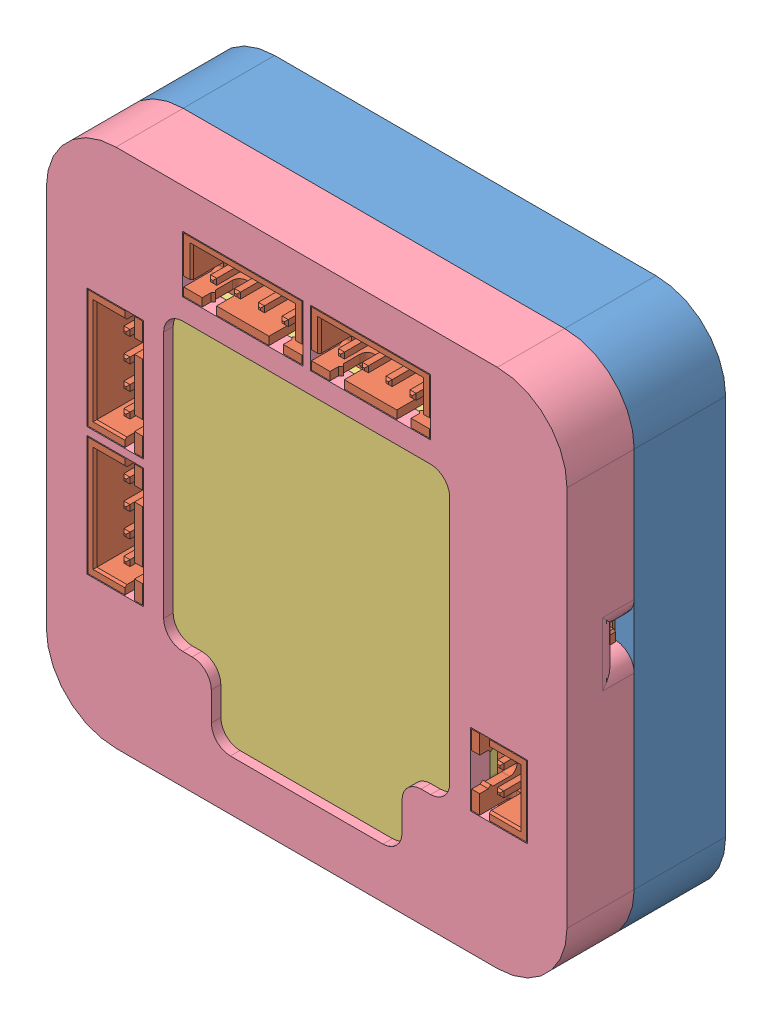
SolidWorks assembly BaroAxel_Brain_VerticalJST_Assembly_Full, configuration Default. Lengths in mm.
Overall size (54.6 54.6 16.64).
4 component instances, 4 part files, 11 mates.
Components (placement in the parent):
- BaroAxel_Brain_VerticalJST_Bottom-1: BaroAxel_Brain_VerticalJST_Bottom [Default] at (34.5375 -20.9006 -0.32) size (54.6 54.6 9.59)
- BaroAxel_Brain_VerticalJST_PCB-1: BaroAxel_Brain_VerticalJST_PCB [Default] at (-138.2825 120.8294 -0.32) size (50.8 50 10.4)
- BaroAxel_Brain_VerticalJST_Glass-1: BaroAxel_Brain_VerticalJST_Glass [Default] at (19.6826 10.3033 4.82) x (0 -1 0) z (0 0 1) size (40 33 2.5)
- BaroAxel_Brain_VerticalJST_Top-1: BaroAxel_Brain_VerticalJST_Top [Default] at (34.5375 -20.9006 -0.32) size (54.6 54.6 7.05)
Mates (geometry in assembly coordinates):
- Concentric1: concentric aligned: cylinder of BaroAxel_Brain_VerticalJST_Bottom-1 through (-10.4625 -15.9006 -8.32) axis (0 0 1) radius 2.15; cylinder of BaroAxel_Brain_VerticalJST_PCB-1 through (-10.4625 -15.9006 -1.115) axis (0 0 1) radius 2.15
- Concentric2: concentric aligned: cylinder of BaroAxel_Brain_VerticalJST_Bottom-1 through (29.5375 24.0994 -8.32) axis (0 0 1) radius 2.15; cylinder of BaroAxel_Brain_VerticalJST_PCB-1 through (29.5375 24.0994 -1.115) axis (0 0 1) radius 2.15
- LimitDistance1: limit distance = 0 mm anti-aligned: plane of BaroAxel_Brain_VerticalJST_PCB-1 through (9.5375 4.0994 -0.32) normal (0 0 -1); plane of BaroAxel_Brain_VerticalJST_Bottom-1 through (-10.5625 -16.0006 -0.32) normal (0 0 1)
- Coincident8: coincident aligned: plane of BaroAxel_Brain_VerticalJST_Bottom-1 through (36.8375 -15.9006 1.27) normal (1 0 0); plane of BaroAxel_Brain_VerticalJST_Top-1 through (36.8375 -15.9006 1.27) normal (1 0 0)
- Coincident9: coincident aligned: plane of BaroAxel_Brain_VerticalJST_Bottom-1 through (29.5375 31.3994 1.27) normal (0 1 0); plane of BaroAxel_Brain_VerticalJST_Top-1 through (29.5375 31.3994 1.27) normal (0 1 0)
- LimitDistance3: limit distance = 0 mm anti-aligned: plane of BaroAxel_Brain_VerticalJST_Top-1 through (-10.4625 24.0994 1.27) normal (0 0 -1); plane of BaroAxel_Brain_VerticalJST_Bottom-1 through (-10.4625 24.0994 1.27) normal (0 0 1)
- Coincident11: coincident anti-aligned: plane of BaroAxel_Brain_VerticalJST_Glass-1 through (17.5375 -19.4006 7.32) normal (0 -1 0); plane of BaroAxel_Brain_VerticalJST_Top-1 through (17.5375 -19.4006 7.32) normal (0 1 0)
- Coincident12: coincident anti-aligned: plane of BaroAxel_Brain_VerticalJST_Glass-1 through (26.0375 17.0994 7.32) normal (1 0 0); plane of BaroAxel_Brain_VerticalJST_Top-1 through (26.0375 17.0994 7.32) normal (-1 0 0)
- Coincident13: coincident anti-aligned: plane of BaroAxel_Brain_VerticalJST_Glass-1 through (17.5375 -19.4006 7.32) normal (0 -1 0); plane of BaroAxel_Brain_VerticalJST_Top-1 through (17.5375 -19.4006 7.32) normal (0 1 0)
- Coincident14: coincident anti-aligned: plane of BaroAxel_Brain_VerticalJST_Glass-1 through (-6.9625 -8.9006 7.32) normal (-1 0 0); plane of BaroAxel_Brain_VerticalJST_Top-1 through (-6.9625 -8.9006 7.32) normal (1 0 0)
- LimitDistance4: limit distance = 0 mm anti-aligned: plane of BaroAxel_Brain_VerticalJST_Glass-1 through (-3.4625 17.0994 7.32) normal (0 0 1); plane of BaroAxel_Brain_VerticalJST_Top-1 through (-3.4625 -8.9006 7.32) normal (0 0 -1)
